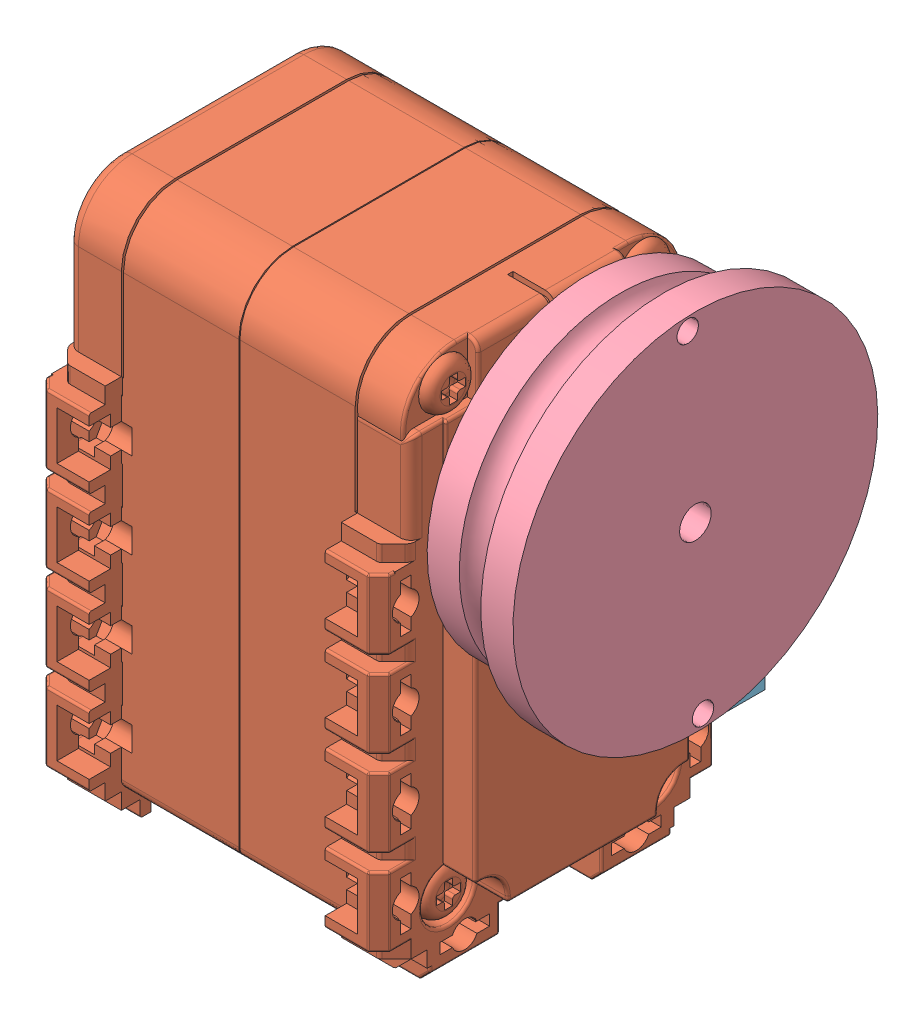
SolidWorks assembly AX12_Base, configuration Default. Lengths in mm.
Overall size (48.5 56.25 36.75).
6 component instances, 5 part files, 3 mates.
Components (placement in the parent):
- AX12-1: AX12 [Default] at (27.2822 31.9817 29.8324) size (48.5 56.25 35.5)
  - ax12_wheel-1: ax12_wheel [Default] at (35.6652 29.55 -1.771) x (0 0.99898 0.045152) z (0 0.045152 -0.99898) size (22 14.85 22)
  - ax12_box-1: ax12_box [Default] at (16.6652 17.55 -1.771) x (0 -1 0) z (0 0 -1) size (50 38.01 32)
  - ax12_cog-1: ax12_cog [Default] at origin size (1 1 1)
  - servoPulleyRX28-1: servoPulleyRX28 [Default] at (43.1652 29.55 -1.771) x (0 -0.99898 -0.045152) z (-1 0 0) size (34 34 10)
- AX12Base-1: AX12Base [Default] at (43.9475 46.7817 9.0614) x (0 1 0) z (1 0 0) size (25 9 38)
Mates (geometry in assembly coordinates):
- Concentric5: concentric: cylinder of AX12-1/ax12_box-1 through (53.9475 54.7817 14.5614) axis (1 0 0) radius 1.25; cylinder of AX12Base-1 through (61.9475 54.7817 14.5614) axis (1 0 0) radius 2
- Coincident3: coincident: plane of AX12-1/ax12_box-1 through (59.9475 73.0317 15.0614) normal (1 0 0); plane of AX12Base-1 through (59.9475 49.5718 19.3943) normal (-1 0 0)
- Concentric6: concentric aligned: cylinder of AX12-1/ax12_box-1 through (33.9475 38.7817 14.5614) axis (-1 0 0) radius 1.25; cylinder of AX12Base-1 through (27.9475 38.7817 14.5614) axis (-1 0 0) radius 1
